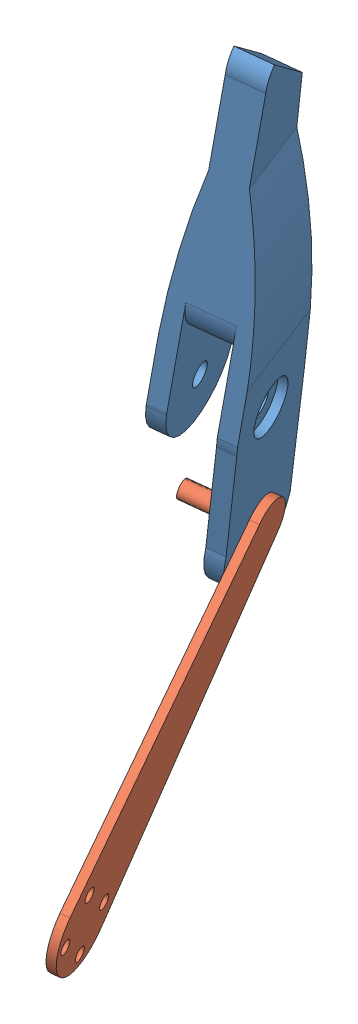
SolidWorks assembly low_leg, configuration Default. Lengths in mm.
Overall size (56.49 185 132.33).
2 component instances, 2 part files, 2 mates.
Components (placement in the parent):
- Lower_leg-1: Lower_leg [Default] at (-90.5421 184.8083 51.6799) x (0.331414 0.614511 0.715919) z (0.941739 -0.169318 -0.290617) size (97.9 88.84 20.12)
- suspension rod-2: suspension rod [Default] at (-82.9696 46.5544 101.7122) x (-0.072733 0.741087 -0.667457) z (-0.941739 0.169318 0.290617) size (91 20 17)
Mates (geometry in assembly coordinates):
- Concentric7: concentric aligned: cylinder of Lower_leg-1 through (-94.0749 103.1519 53.3966) axis (0.941739 -0.169318 -0.290617) radius 2; cylinder of suspension rod-2 through (-104.4341 105.0144 56.5933) axis (0.941739 -0.169318 -0.290617) radius 2
- Coincident10: coincident anti-aligned: plane of Lower_leg-1 through (-68.5686 210.1673 59.9367) normal (0.941739 -0.169318 -0.290617); plane of suspension rod-2 through (-84.853 46.8931 102.2934) normal (-0.941739 0.169318 0.290617)
